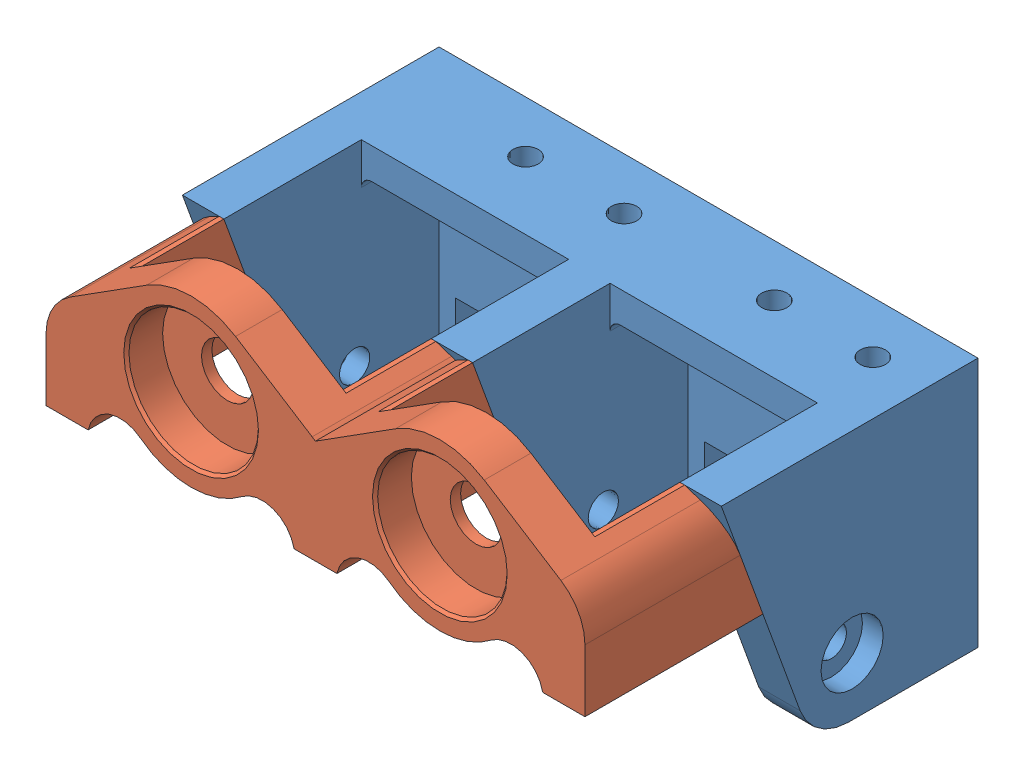
SolidWorks assembly reach adjusted base, configuration Default. Lengths in mm.
Overall size (52 29.34 37.93).
2 component instances, 2 part files, 4 mates.
Components (placement in the parent):
- double main body base chop-1: double main body base chop [Default] at (-2.4638 0.4715 -5.6024) size (52 24.18 24.76)
- double main body magnet chop-1: double main body magnet chop [Default] at (-2.4638 -19.7367 4.8202) size (52 16.17 17.17)
Mates (geometry in assembly coordinates):
- Parallel1: parallel anti-aligned: plane of double main body base chop-1 through (19.8821 27.3214 29.5488) normal (0 0 -1); plane of double main body magnet chop-1 through (19.8821 34.6053 67.4714) normal (0 0 1)
- Distance1: distance = 5 mm: line of double main body magnet chop-1 through (43.8821 32.4482 52.4913) axis (0 0 1); line of double main body base chop-1 through (43.8821 37.4482 29.5488) axis (0 0 1)
- Distance2: distance = 10 mm: point of double main body base chop-1; point of double main body magnet chop-1
- Coincident5: coincident aligned: plane of double main body base chop-1 through (43.8821 37.9433 43.5488) normal (1 0 0); plane of double main body magnet chop-1 through (43.8821 17.7351 53.9714) normal (1 0 0)
